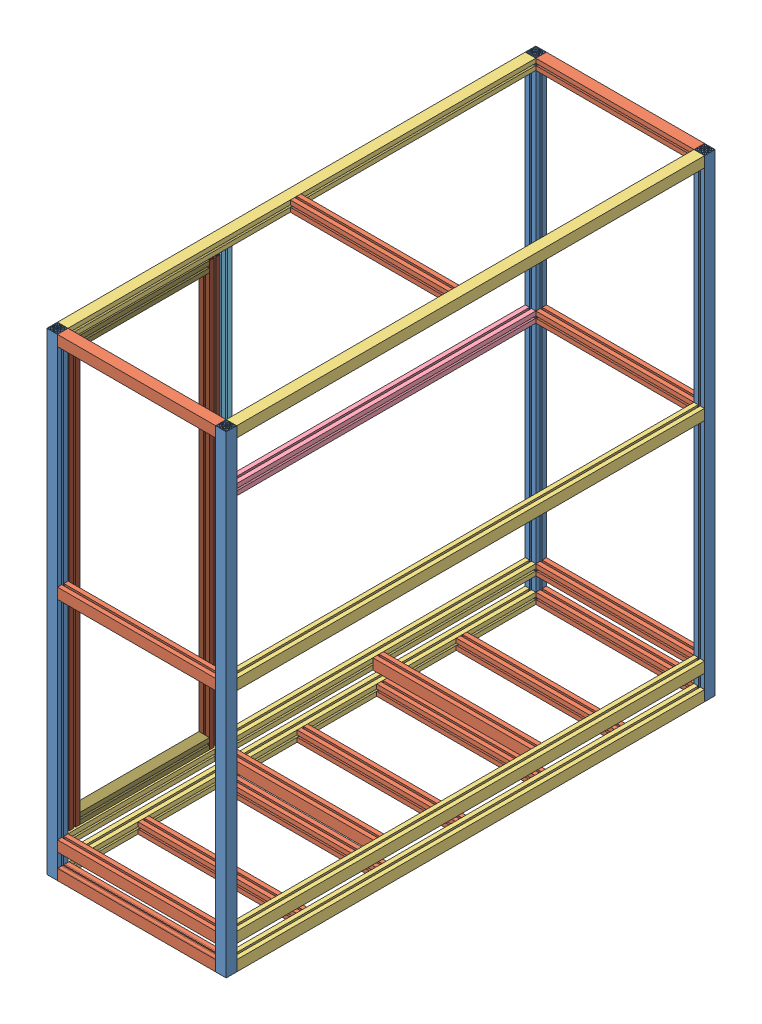
SolidWorks assembly big_cage, configuration Default. Lengths in mm.
Overall size (776.16 2012.95 2080.73).
61 component instances, 12 part files, 38 mates.
Components (placement in the parent):
- 20.1028 45X45 G_79_25in-1: 20.1028 45X45 G_79_25in [Default] at (640.3138 2098.0018 1575.8254) x (0 0 -1) z (0 -1 0) size (45 45 2012.95)
- 20.1028 45X45 G_29in-1: 20.1028 45X45 G_29in [inner] at (617.813 1144.0411 1575.8254) x (0 0 -1) z (-1 0 0) size (45 45 673.1)
- 20.1028 45X45 G_29in-2: 20.1028 45X45 G_29in [Default] at (617.813 2075.5023 1575.8256) x (0 -1 0) z (-1 0 0) size (45 45 673.1)
- 20.1028 45X45 G_29in-7: 20.1028 45X45 G_29in [inner] at (617.813 212.5811 1575.8254) x (0 0 -1) z (-1 0 0) size (45 45 673.1)
- 20.1028 45X45 G_29in-10: 20.1028 45X45 G_29in [inner] at (617.813 107.5511 1575.8254) x (0 0 -1) z (-1 0 0) size (45 45 673.1)
- 20.1028 45X45 G_79_25in-2: 20.1028 45X45 G_79_25in [Default] at (-77.7877 85.0518 1575.8254) x (0 0 -1) z (0 1 0) size (45 45 2012.95)
- 20.1028 45X45 G_78-38in-1: 20.1028 45X45 G_78-38in [Default] at (640.3136 2075.5025 1553.3249) x (-1 0 0) z (0 0 -1) size (45 45 1990.73)
- 20.1028 45X45 G_78-38in-2: 20.1028 45X45 G_78-38in [inner] at (640.3136 1144.0425 1553.3249) x (-1 0 0) z (0 0 -1) size (45 45 1990.73)
- 20.1028 45X45 G_78-38in-3: 20.1028 45X45 G_78-38in [inner] at (640.3136 212.5825 1553.3249) x (-1 0 0) z (0 0 -1) size (45 45 1990.73)
- 20.1028 45X45 G_78-38in-5: 20.1028 45X45 G_78-38in [inner] at (640.3136 107.5525 1553.3249) x (-1 0 0) z (0 0 -1) size (45 45 1990.73)
- 20.1028 45X45 G_29in-12: 20.1028 45X45 G_29in [Default] at (-55.287 2075.5023 -459.9008) x (0 -1 0) z (1 0 0) size (45 45 673.1)
- 20.1028 45X45 G_79_25in-3: 20.1028 45X45 G_79_25in [Default] at (640.3137 85.0518 -459.9007) x (0 0 1) z (0 1 0) size (45 45 2012.95)
- 20.1028 45X45 G_79_25in-4: 20.1028 45X45 G_79_25in [Default] at (-77.7877 2098.0018 -459.9006) x (0 0 1) z (0 -1 0) size (45 45 2012.95)
- 20.1028 45X45 G_29in-13: 20.1028 45X45 G_29in [inner] at (-55.287 1144.0411 -459.9006) x (0 0 1) z (1 0 0) size (45 45 673.1)
- 20.1028 45X45 G_29in-14: 20.1028 45X45 G_29in [inner] at (-55.287 212.5811 -459.9006) x (0 0 1) z (1 0 0) size (45 45 673.1)
- 20.1028 45X45 G_29in-15: 20.1028 45X45 G_29in [inner] at (-55.287 107.5511 -459.9006) x (0 0 1) z (1 0 0) size (45 45 673.1)
- 20.1028 45X45 G_78-38in-7: 20.1028 45X45 G_78-38in [Default] at (-77.7875 2075.5025 -437.4001) x (1 0 0) z (0 0 1) size (45 45 1990.73)
- 20.1028 45X45 G_78-38in-8: 20.1028 45X45 G_78-38in [inner] at (-77.7875 212.5825 -437.4001) x (1 0 0) z (0 0 1) size (45 45 1990.73)
- 20.1028 45X45 G_78-38in-9: 20.1028 45X45 G_78-38in [inner] at (-77.7875 107.5525 -437.4001) x (1 0 0) z (0 0 1) size (45 45 1990.73)
- 20.1028 45X45 G_57in-1: 20.1028 45X45 G_57in [inner] at (-77.7875 1144.0425 -437.4001) x (1 0 0) z (0 0 1) size (45 45 1292.86)
- 20.1028 45X45 G_71_57in-1: 20.1028 45X45 G_71_57in [inner] at (-77.7875 2052.9598 877.9606) x (1 0 0) z (0 -1 0) size (45 45 1817.88)
- 21.1378 HINGE L 45_45 LEFT HAND-1: 21.1378 HINGE L 45_45 LEFT HAND [Default] at (-105.7413 1843.4518 1550.8249) x (-0.995759 0 -0.091997) z (0 1 0) size (42.93 28.99 65.5)
  - 21.1096 HINGE PIN-1: 21.1096 HINGE PIN [Default] at origin size (6.07 6.07 65)
  - 21.1096 HINGE WASHER-1: 21.1096 HINGE WASHER [Default] at (0 0 31.75) x (0.995445 -0.095341 0) z (0 0 1) size (10 10 1.5)
  - 21.1378 HINGE L 45 AL BLOCK-1: 21.1378 HINGE L 45 AL BLOCK [Default] at (0 0 15.75) x (-0.995759 -0.091997 0) z (0 0 1) size (42 12 32)
  - 21.1378 HINGE L 45 AL BLOCK-2: 21.1378 HINGE L 45 AL BLOCK [Default] at (0 0 49.25) x (-0.995759 -0.091997 0) z (0 0 -1) size (42 12 32)
  - 21.1506 M6x16 C'SUNK-1: 21.1506 M6x16 C'SUNK [Default] at (-26.7015 -4.4754 7.75) x (0.995759 0.091997 0) z (0.091997 -0.995759 0) size (12 12 16)
  - 21.1506 M6x16 C'SUNK-2: 21.1506 M6x16 C'SUNK [Default] at (-27.0695 -0.4924 41.25) x (0.995759 0.091997 0) z (-0.091997 0.995759 0) size (12 12 16)
  - 21.1506 M6x16 C'SUNK-3: 21.1506 M6x16 C'SUNK [Default] at (-27.0695 -0.4924 57.25) x (0.995759 0.091997 0) z (-0.091997 0.995759 0) size (12 12 16)
  - 21.1506 M6x16 C'SUNK-4: 21.1506 M6x16 C'SUNK [Default] at (-26.7015 -4.4754 23.75) x (0.995689 0.091991 0.011859) z (0.091997 -0.995759 0) size (12 12 16)
  - 21.1330 M6 SQUARE NUT-1: 21.1330 M6 SQUARE NUT [Default] at (-26.2415 -9.4542 41.25) x (0.995759 0.091997 0) z (-0.091997 0.995759 0) size (13 13 5.5)
  - 21.1330 M6 SQUARE NUT-2: 21.1330 M6 SQUARE NUT [Default] at (-26.2415 -9.4542 57.25) x (0 0 1) z (-0.091997 0.995759 0) size (13 13 5.5)
  - 21.1330 M6 SQUARE NUT-3: 21.1330 M6 SQUARE NUT [Default] at (-27.5295 4.4864 7.75) x (0.995759 0.091997 0) z (0.091997 -0.995759 0) size (13 13 5.5)
  - 21.1330 M6 SQUARE NUT-4: 21.1330 M6 SQUARE NUT [Default] at (-27.5295 4.4864 23.75) x (0.995759 0.091997 0) z (0.091997 -0.995759 0) size (13 13 5.5)
- 21.1378 HINGE L 45_45 LEFT HAND-2: 21.1378 HINGE L 45_45 LEFT HAND [Default] at (-102.0369 452.7318 1550.8249) x (-0.995759 0 0.091997) z (0 -1 0) size (42.93 28.99 65.5)
  - 21.1096 HINGE PIN-1: 21.1096 HINGE PIN [Default] at origin size (6.07 6.07 65)
  - 21.1096 HINGE WASHER-1: 21.1096 HINGE WASHER [Default] at (0 0 31.75) x (0.995445 -0.095341 0) z (0 0 1) size (10 10 1.5)
  - 21.1378 HINGE L 45 AL BLOCK-1: 21.1378 HINGE L 45 AL BLOCK [Default] at (0 0 15.75) x (-0.995759 -0.091997 0) z (0 0 1) size (42 12 32)
  - 21.1378 HINGE L 45 AL BLOCK-2: 21.1378 HINGE L 45 AL BLOCK [Default] at (0 0 49.25) x (-0.995759 -0.091997 0) z (0 0 -1) size (42 12 32)
  - 21.1506 M6x16 C'SUNK-1: 21.1506 M6x16 C'SUNK [Default] at (-26.7015 -4.4754 7.75) x (0.995759 0.091997 0) z (0.091997 -0.995759 0) size (12 12 16)
  - 21.1506 M6x16 C'SUNK-2: 21.1506 M6x16 C'SUNK [Default] at (-27.0695 -0.4924 41.25) x (0.995759 0.091997 0) z (-0.091997 0.995759 0) size (12 12 16)
  - 21.1506 M6x16 C'SUNK-3: 21.1506 M6x16 C'SUNK [Default] at (-27.0695 -0.4924 57.25) x (0.995759 0.091997 0) z (-0.091997 0.995759 0) size (12 12 16)
  - 21.1506 M6x16 C'SUNK-4: 21.1506 M6x16 C'SUNK [Default] at (-26.7015 -4.4754 23.75) x (0.995689 0.091991 0.011859) z (0.091997 -0.995759 0) size (12 12 16)
  - 21.1330 M6 SQUARE NUT-1: 21.1330 M6 SQUARE NUT [Default] at (-26.2415 -9.4542 41.25) x (0.995759 0.091997 0) z (-0.091997 0.995759 0) size (13 13 5.5)
  - 21.1330 M6 SQUARE NUT-2: 21.1330 M6 SQUARE NUT [Default] at (-26.2415 -9.4542 57.25) x (0 0 1) z (-0.091997 0.995759 0) size (13 13 5.5)
  - 21.1330 M6 SQUARE NUT-3: 21.1330 M6 SQUARE NUT [Default] at (-27.5295 4.4864 7.75) x (0.995759 0.091997 0) z (0.091997 -0.995759 0) size (13 13 5.5)
  - 21.1330 M6 SQUARE NUT-4: 21.1330 M6 SQUARE NUT [Default] at (-27.5295 4.4864 23.75) x (0.995759 0.091997 0) z (0.091997 -0.995759 0) size (13 13 5.5)
- door-1: door [Default] at (-77.7875 2046.6518 928.3756) x (1 0 0) z (0 -1 0) size (45 642.45 1803.4)
  - 20.1028 45X45 G_71_5in-1: 20.1028 45X45 G_71_5in [inner] at origin size (45 45 1803.4)
  - 20.1028 45X45 G_18_125in-2: 20.1028 45X45 G_18_125in [Default] at (-0.0002 574.9493 22.4995) x (0 0 1) z (0 -1 0) size (45 45 552.45)
  - 20.1028 45X45 G_18_125in-4: 20.1028 45X45 G_18_125in [Default] at (-0.0002 574.9493 1780.8995) x (0 0 1) z (0 -1 0) size (45 45 552.45)
  - 20.1028 45X45 G_71_5in-2: 20.1028 45X45 G_71_5in [inner] at (0 597.4486 1803.4) x (1 0 0) z (0 0 -1) size (45 45 1803.4)
- 20.1028 45X45 G_29in-16: 20.1028 45X45 G_29in [inner] at (617.813 212.5811 904.7504) x (0 0 -1) z (-1 0 0) size (45 45 673.1)
- 20.1028 45X45 G_29in-17: 20.1028 45X45 G_29in [inner] at (617.813 212.5811 233.6754) x (0 0 -1) z (-1 0 0) size (45 45 673.1)
- 20.1028 45X45 G_29in-19: 20.1028 45X45 G_29in [inner] at (-55.287 2075.5011 584.9734) x (0 0 1) z (1 0 0) size (45 45 673.1)
- 20.1028 45X45 G_29in-20: 20.1028 45X45 G_29in [inner] at (-55.287 107.5511 -121.3215) x (0 0 1) z (1 0 0) size (45 45 673.1)
- 20.1028 45X45 G_29in-21: 20.1028 45X45 G_29in [inner] at (-55.287 107.5511 217.2577) x (0 0 1) z (1 0 0) size (45 45 673.1)
- 20.1028 45X45 G_29in-22: 20.1028 45X45 G_29in [inner] at (-55.287 107.5511 555.8369) x (0 0 1) z (1 0 0) size (45 45 673.1)
- 20.1028 45X45 G_29in-23: 20.1028 45X45 G_29in [inner] at (-55.287 107.5511 894.416) x (0 0 1) z (1 0 0) size (45 45 673.1)
- 20.1028 45X45 G_29in-24: 20.1028 45X45 G_29in [inner] at (-55.287 107.5511 1232.9952) x (0 0 1) z (1 0 0) size (45 45 673.1)
- 20.1028 45X45 G_29in-25: 20.1028 45X45 G_29in [inner] at (-55.287 107.5511 1571.5744) x (0 0 1) z (1 0 0) size (45 45 673.1)
Mates (geometry in assembly coordinates):
- Coincident4: coincident anti-aligned: line of 20.1028 45X45 G_79_25in-1 through (617.813 85.0518 1553.3249) axis (0 1 0); line of 20.1028 45X45 G_29in-1 through (617.813 1166.5418 1553.3249) axis (0 -1 0)
- Coincident5: coincident anti-aligned: line of 20.1028 45X45 G_79_25in-1 through (617.813 85.0518 1553.3249) axis (0 1 0); line of 20.1028 45X45 G_29in-2 through (617.813 2098.0018 1553.3249) axis (0 -1 0)
- Coincident6: coincident aligned: line of 20.1028 45X45 G_79_25in-1 through (617.8131 2098.0018 1598.3249) axis (0 0 -1); line of 20.1028 45X45 G_29in-2 through (617.8131 2098.0018 1598.3249) axis (0 0 -1)
- Coincident7: coincident: plane of 20.1028 45X45 G_79_25in-1 through (617.813 85.0518 1575.8254) normal (-1 0 0); line of 20.1028 45X45 G_29in-1 through (617.813 1166.5418 1571.5749) axis (0 0 -1)
- Coincident8: coincident anti-aligned: plane of 20.1028 45X45 G_29in-1 through (-55.287 1166.5418 1575.8254) normal (0 1 0)
- Coincident13: coincident anti-aligned: line of 20.1028 45X45 G_79_25in-1 through (617.813 85.0518 1553.3249) axis (0 1 0); line of 20.1028 45X45 G_29in-7 through (617.813 235.0818 1553.3249) axis (0 -1 0)
- Coincident14: coincident anti-aligned: plane of 20.1028 45X45 G_29in-7 through (-55.287 235.0818 1575.8254) normal (0 1 0)
- Coincident19: coincident aligned: line of 20.1028 45X45 G_79_25in-1 through (617.8131 85.0518 1598.3249) axis (0 1 0); line of 20.1028 45X45 G_29in-7 through (617.8131 190.0818 1598.3249) axis (0 1 0)
- Coincident20: coincident anti-aligned: line of 20.1028 45X45 G_79_25in-1 through (617.813 85.0518 1553.3249) axis (0 1 0); line of 20.1028 45X45 G_29in-10 through (617.813 130.0518 1553.3249) axis (0 -1 0)
- Coincident21: coincident aligned: line of 20.1028 45X45 G_79_25in-1 through (617.8131 85.0518 1598.3249) axis (0 1 0); line of 20.1028 45X45 G_29in-10 through (617.8131 85.0518 1598.3249) axis (0 1 0)
- Coincident24: coincident anti-aligned: line of 20.1028 45X45 G_79_25in-1 through (617.813 85.0518 1571.5749) axis (0 0 -1); line of 20.1028 45X45 G_29in-10 through (617.813 85.0518 1553.3249) axis (0 0 1)
- Coincident25: coincident aligned: line of 20.1028 45X45 G_79_25in-1 through (644.563 2098.0018 1553.3249) axis (1 0 0); line of 20.1028 45X45 G_72in-1 through (617.813 2098.0018 1553.3249) axis (1 0 0)
- Coincident26: coincident anti-aligned: line of 20.1028 45X45 G_79_25in-1 through (662.813 85.0518 1553.3249) axis (0 1 0); line of 20.1028 45X45 G_72in-1 through (662.813 2098.0018 1553.3249) axis (0 -1 0)
- Coincident28: coincident anti-aligned: line of 20.1028 45X45 G_79_25in-1 through (662.813 85.0518 1553.3249) axis (0 1 0); line of 20.1028 45X45 G_72in-2 through (662.813 1166.5418 1553.3249) axis (0 -1 0)
- Coincident29: coincident aligned: plane of 20.1028 45X45 G_29in-1 through (-55.287 1166.5418 1575.8254) normal (0 1 0); plane of 20.1028 45X45 G_72in-2 through (640.3136 1166.5418 -437.4001) normal (0 1 0)
- Coincident30: coincident anti-aligned: line of 20.1028 45X45 G_79_25in-1 through (662.813 85.0518 1553.3249) axis (0 1 0); line of 20.1028 45X45 G_78-38in-3 through (662.813 235.0818 1553.3249) axis (0 -1 0)
- Coincident32: coincident aligned: line of 20.1028 45X45 G_29in-7 through (-55.287 235.0818 1553.3249) axis (1 0 0); line of 20.1028 45X45 G_78-38in-3 through (617.813 235.0818 1553.3249) axis (1 0 0)
- Coincident33: coincident anti-aligned: line of 20.1028 45X45 G_79_25in-1 through (662.813 85.0518 1553.3249) axis (0 1 0); line of 20.1028 45X45 G_72in-5 through (662.813 130.0518 1553.3249) axis (0 -1 0)
- Coincident34: coincident aligned: line of 20.1028 45X45 G_29in-10 through (-55.287 130.0518 1553.3249) axis (1 0 0); line of 20.1028 45X45 G_72in-5 through (617.813 130.0518 1553.3249) axis (1 0 0)
- Coincident48: coincident anti-aligned: plane of 20.1028 45X45 G_79_25in-2 through (-77.7877 2098.0018 1553.3249) normal (0 0 -1); plane of 21.1378 HINGE L 45_45 LEFT HAND-2/21.1378 HINGE L 45 AL BLOCK-2 through (-74.5369 403.4818 1553.3249) normal (0 0 1)
- Coincident49: coincident aligned: line of 20.1028 45X45 G_79_25in-2 through (-82.0369 2098.0018 1553.3249) axis (0 -1 0); line of 21.1378 HINGE L 45_45 LEFT HAND-2/21.1378 HINGE L 45 AL BLOCK-2 through (-82.0369 419.4818 1553.3249) axis (0 -1 0)
- Distance1: distance = 152.4 mm: line of 21.1378 HINGE L 45_45 LEFT HAND-2/21.1378 HINGE L 45 AL BLOCK-2 through (-68.5369 387.4818 1548.3249) axis (-1 0 0)
- Coincident53: coincident: point of 20.1028 45X45 G_29in-13; point of 20.1028 45X45 G_57in-1
- Coincident54: coincident: line of 20.1028 45X45 G_79_25in-4 through (-100.287 85.0518 -437.4001) axis (0 1 0); line of 20.1028 45X45 G_57in-1 through (-100.287 1166.5418 -437.4001) axis (0 -1 0)
- Coincident55: coincident anti-aligned: plane of 20.1028 45X45 G_79_25in-2 through (-77.7877 2098.0018 1553.3249) normal (0 0 -1); plane of 21.1378 HINGE L 45_45 LEFT HAND-1/21.1378 HINGE L 45 AL BLOCK-1 through (-91.2413 1859.2018 1553.3249) normal (0 0 1)
- Perpendicular1: perpendicular: line of 20.1028 45X45 G_79_25in-2 through (-100.2869 2098.0018 1553.3249) axis (0 -1 0); line of 21.1378 HINGE L 45_45 LEFT HAND-1/21.1378 HINGE L 45 AL BLOCK-1 through (-100.2869 1843.2018 1553.3249) axis (1 0 0)
- Coincident57: coincident: line of 20.1028 45X45 G_79_25in-2 through (-100.2869 2098.0018 1553.3249) axis (0 -1 0); line of 21.1378 HINGE L 45_45 LEFT HAND-1/21.1378 HINGE L 45 AL BLOCK-1 through (-100.2869 1843.2018 1553.3249) axis (0 1 0)
- Distance2: distance = 177.8 mm: line of 21.1378 HINGE L 45_45 LEFT HAND-1/21.1378 HINGE L 45 AL BLOCK-1 through (-85.7413 1875.2018 1553.3249) axis (1 0 0); line of 20.1028 45X45 G_78-38in-7 through (-100.287 2053.0018 1553.3249) axis (1 0 0)
- Coincident68: coincident aligned: line of 20.1028 45X45 G_78-38in-8 through (-100.2869 235.0818 1553.3249) axis (0 0 -1); line of 20.1028 45X45 G_71_57in-1 through (-100.287 235.0818 900.4599) axis (0 0 -1)
- Coincident69: coincident: line of 20.1028 45X45 G_78-38in-8 through (-55.287 235.0818 1553.3249) axis (0 0 -1); point of 20.1028 45X45 G_71_57in-1
- Coincident71: coincident: point of 20.1028 45X45 G_57in-1; plane of 20.1028 45X45 G_71_57in-1 through (-77.7875 235.0818 855.4599) normal (0 0 -1)
- Coincident73: coincident: line of 21.1378 HINGE L 45_45 LEFT HAND-1/21.1378 HINGE L 45 AL BLOCK-2 through (-100.2869 1908.7018 1548.3249) axis (0 -1 0); line of door-1/20.1028 45X45 G_71_5in-2 through (-100.2869 2046.6518 1548.3249) axis (0 -1 0)
- Coincident74: coincident anti-aligned: plane of 21.1378 HINGE L 45_45 LEFT HAND-1/21.1378 HINGE L 45 AL BLOCK-2 through (-100.2869 1892.7018 1548.3249) normal (0 0 -1); plane of door-1/20.1028 45X45 G_71_5in-2 through (-77.7875 2046.6518 1548.3249) normal (0 0 1)
- Distance4: distance = 6.35 mm: plane of door-1/20.1028 45X45 G_18_125in-2 through (-77.7877 2046.6518 950.8749) normal (0 1 0); plane of 20.1028 45X45 G_78-38in-7 through (-77.7875 2053.0018 1553.3249) normal (0 -1 0)
- Parallel10: parallel aligned: plane of 20.1028 45X45 G_78-38in-7 through (-77.7875 2098.0018 1553.3249) normal (0 1 0); plane of 20.1028 45X45 G_29in-19 through (617.813 2098.0018 584.9733) normal (0 1 0)
- Coincident89: coincident: plane of 20.1028 45X45 G_78-38in-7 through (-77.7875 2098.0018 1553.3249) normal (0 1 0); plane of 20.1028 45X45 G_29in-19 through (617.813 2098.0018 584.9733) normal (0 1 0)
- Parallel14: parallel: plane of assembly through (0 0 557.9624) normal (0 0 -1); plane of 20.1028 45X45 G_29in-19 through (-55.287 2075.5011 584.9734) normal (0 0 1); plane of assembly
- Coincident93: coincident: line of 20.1028 45X45 G_78-38in-7 through (-55.287 2098.0018 1553.3249) axis (0 0 -1); moEndPointRef_w of 20.1028 45X45 G_29in-19
